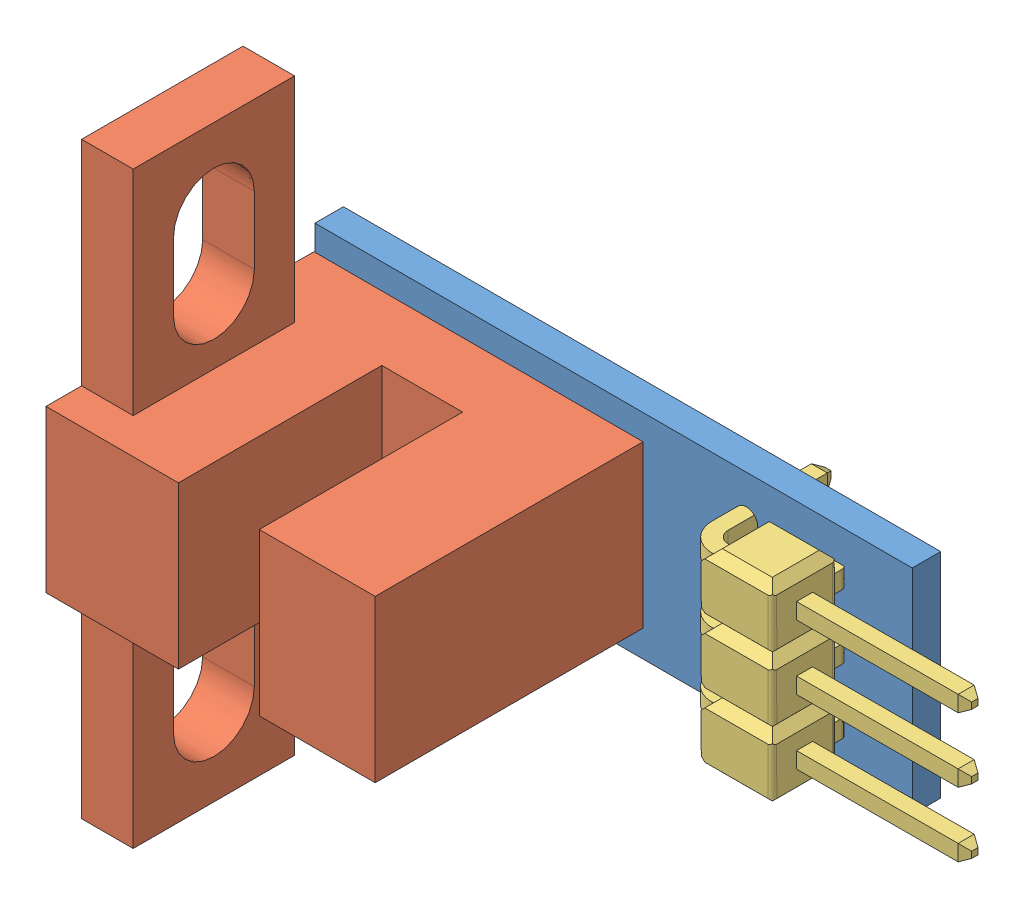
SolidWorks assembly Assem2, configuration Default. Lengths in mm.
Overall size (27.79 23.15 13.77).
3 component instances, 3 part files, 3 mates.
Components (placement in the parent):
- light interrupter-1: light interrupter [Default] at (-28.3605 -96.0125 19.17) size (23.5 8.4 2.42)
- OPB840L51-1: OPB840L51 [Default] at (3.5735 12.3185 19.17) x (1 0 0) z (0 -1 0) size (12.95 13.04 23.15)
- Pin Header 1x3 TH Angle Pitch 2.54mm-1: Pin Header 1x3 TH Angle Pitch 2.54mm [Default] at (14.0957 9.7707 19.1411) x (0 1 0) z (0 0 1) size (7.63 11.11 6.29)
Mates (geometry in assembly coordinates):
- Concentric1: concentric anti-aligned: circle of light interrupter-1; circle of OPB840L51-1
- Coincident1: coincident anti-aligned: plane of light interrupter-1 through (-2.8605 8.0875 19.17) normal (0 0 1); plane of OPB840L51-1 through (3.5735 12.3185 19.17) normal (0 0 -1)
- Lock1: lock: unknown of light interrupter-1; unknown of Pin Header 1x3 TH Angle Pitch 2.54mm-1
